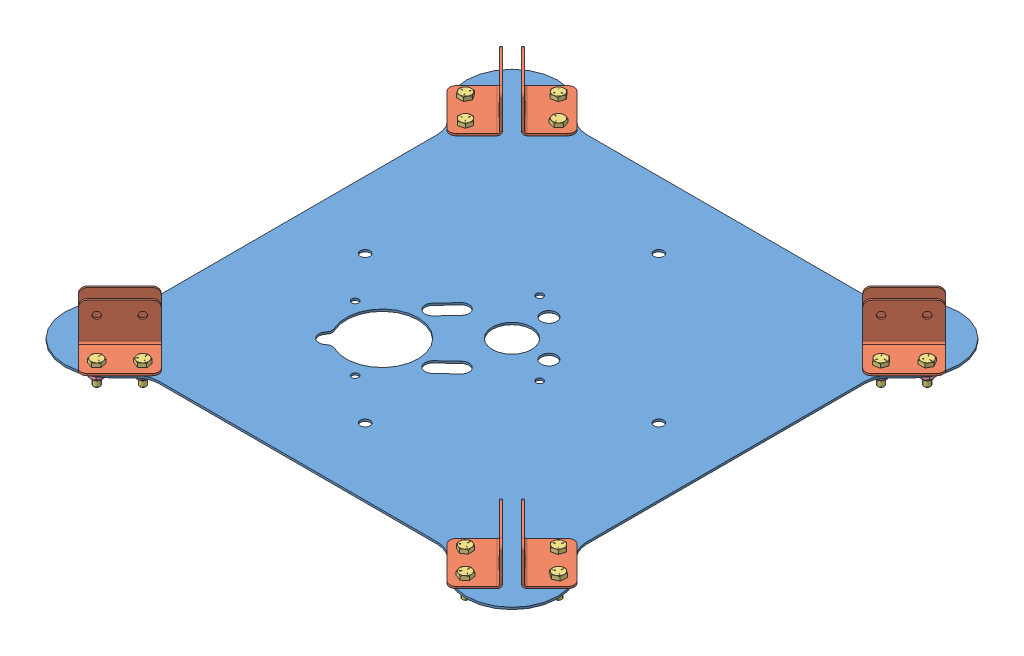
SolidWorks assembly GE-22413, configuration Default. Lengths in mm.
Overall size (485.29 55.25 485.29).
41 component instances, 4 part files, 91 mates.
Components (placement in the parent):
- GE-22412-1: GE-22412 [Default] at origin size (479.54 1.99 479.54)
- GE-22301-2: GE-22301 [Default] at (-195.5002 1.9939 186.1607) x (0.707107 0 -0.707107) z (0 1 0) size (57.15 38.1 38.1)
- GE-22301-17: GE-22301 [Default] at (-186.1607 1.9939 195.5002) x (0.707107 0 -0.707107) z (0.707107 0 0.707107) size (57.15 38.1 38.1)
- GE-22301-1: GE-22301 [Default] at (195.5002 1.9939 -186.1607) x (0.707107 0 -0.707107) z (0.707107 0 0.707107) size (57.15 38.1 38.1)
- GE-22301-20: GE-22301 [Default] at (186.1607 1.9939 195.5002) x (-0.707107 0 -0.707107) z (0 1 0) size (57.15 38.1 38.1)
- GE-22301-22: GE-22301 [Default] at (195.5002 1.9939 186.1607) x (0.707107 0 0.707107) z (0 1 0) size (57.15 38.1 38.1)
- GE-22301-25: GE-22301 [Default] at (186.1607 1.9939 -195.5002) x (0.707107 0 -0.707107) z (0 1 0) size (57.15 38.1 38.1)
- GE-22301-27: GE-22301 [Default] at (-186.1607 1.9939 -195.5002) x (0.707107 0 0.707107) z (0 1 0) size (57.15 38.1 38.1)
- GE-22301-29: GE-22301 [Default] at (-195.5002 1.9939 -186.1607) x (-0.707107 0 -0.707107) z (0 1 0) size (57.15 38.1 38.1)
- hex_.25_20_0.75-1: hex_.25_20_0.75 [Default] at (224.686 -3.6493 -179.4255) x (0 -1 0) z (0 0 1) size (23.02 12.83 11.11)
- nylock_.25_20-1: nylock_.25_20 [Default] at (224.686 0 -179.4255) x (1 0 0) z (0 0 -1) size (11.11 7.94 12.83)
- hex_.25_20_0.75-2: hex_.25_20_0.75 [Default] at (202.2354 -3.6493 -156.9749) x (0 -1 0) z (0.188455 0 0.982082) size (23.02 12.83 11.11)
- nylock_.25_20-2: nylock_.25_20 [Default] at (202.2354 0 -156.9749) x (0.982082 0 -0.188455) z (-0.188455 0 -0.982082) size (11.11 7.94 12.83)
- hex_.25_20_0.75-4: hex_.25_20_0.75 [Default] at (179.4255 -3.6493 -224.686) x (0 -1 0) z (0.370156 0 0.92897) size (23.02 12.83 11.11)
- nylock_.25_20-4: nylock_.25_20 [Default] at (179.4255 0 -224.686) x (0.92897 0 -0.370156) z (-0.370156 0 -0.92897) size (11.11 7.94 12.83)
- hex_.25_20_0.75-6: hex_.25_20_0.75 [Default] at (156.9749 -3.6493 -202.2354) x (0 -1 0) z (0.561714 0 0.827332) size (23.02 12.83 11.11)
- nylock_.25_20-6: nylock_.25_20 [Default] at (156.9749 0 -202.2354) x (0.827332 0 -0.561714) z (-0.561714 0 -0.827332) size (11.11 7.94 12.83)
- hex_.25_20_0.75-8: hex_.25_20_0.75 [Default] at (-156.9749 -3.6493 -202.2354) x (0 -1 0) z (0.740013 0 0.672593) size (23.02 12.83 11.11)
- nylock_.25_20-8: nylock_.25_20 [Default] at (-156.9749 0 -202.2354) x (0.672593 0 -0.740013) z (-0.740013 0 -0.672593) size (11.11 7.94 12.83)
- hex_.25_20_0.75-25: hex_.25_20_0.75 [Default] at (-224.686 -3.6493 -179.4255) x (0 -1 0) z (0.879216 0 0.476424) size (23.02 12.83 11.11)
- nylock_.25_20-10: nylock_.25_20 [Default] at (-224.686 0 -179.4255) x (0.476424 0 -0.879216) z (-0.879216 0 -0.476424) size (11.11 7.94 12.83)
- hex_.25_20_0.75-31: hex_.25_20_0.75 [Default] at (-202.2354 -3.6493 -156.9749) x (0 -1 0) z (0.963756 0 0.266785) size (23.02 12.83 11.11)
- nylock_.25_20-12: nylock_.25_20 [Default] at (-202.2354 0 -156.9749) x (0.266785 0 -0.963756) z (-0.963756 0 -0.266785) size (11.11 7.94 12.83)
- hex_.25_20_0.75-28: hex_.25_20_0.75 [Default] at (-224.686 -3.6493 179.4255) x (0 -1 0) z (0.997054 0 0.076699) size (23.02 12.83 11.11)
- nylock_.25_20-14: nylock_.25_20 [Default] at (-224.686 0 179.4255) x (0.076699 0 -0.997054) z (-0.997054 0 -0.076699) size (11.11 7.94 12.83)
- hex_.25_20_0.75-27: hex_.25_20_0.75 [Default] at (-202.2354 -3.6493 156.9749) x (0 -1 0) z (0.997612 0 -0.069065) size (23.02 12.83 11.11)
- nylock_.25_20-16: nylock_.25_20 [Default] at (-202.2354 0 156.9749) x (-0.069065 0 -0.997612) z (-0.997612 0 0.069065) size (11.11 7.94 12.83)
- hex_.25_20_0.75-26: hex_.25_20_0.75 [Default] at (-156.9749 -3.6493 202.2354) x (0 -1 0) z (0.987353 0 -0.158535) size (23.02 12.83 11.11)
- nylock_.25_20-18: nylock_.25_20 [Default] at (-156.9749 0 202.2354) x (-0.158535 0 -0.987353) z (-0.987353 0 0.158535) size (11.11 7.94 12.83)
- hex_.25_20_0.75-30: hex_.25_20_0.75 [Default] at (-179.4255 -3.6493 224.686) x (0 -1 0) z (0.982082 0 -0.188455) size (23.02 12.83 11.11)
- nylock_.25_20-20: nylock_.25_20 [Default] at (-179.4255 0 224.686) x (-0.188455 0 -0.982082) z (-0.982082 0 0.188455) size (11.11 7.94 12.83)
- hex_.25_20_0.75-32: hex_.25_20_0.75 [Default] at (179.4255 -3.6493 224.686) x (0 -1 0) z (0.987353 0 -0.158535) size (23.02 12.83 11.11)
- nylock_.25_20-22: nylock_.25_20 [Default] at (179.4255 0 224.686) x (-0.158535 0 -0.987353) z (-0.987353 0 0.158535) size (11.11 7.94 12.83)
- hex_.25_20_0.75-24: hex_.25_20_0.75 [Default] at (156.9749 -3.6493 202.2354) x (0 -1 0) z (0.997612 0 -0.069065) size (23.02 12.83 11.11)
- nylock_.25_20-24: nylock_.25_20 [Default] at (156.9749 0 202.2354) x (-0.069065 0 -0.997612) z (-0.997612 0 0.069065) size (11.11 7.94 12.83)
- hex_.25_20_0.75-33: hex_.25_20_0.75 [Default] at (224.686 -3.6493 179.4255) x (0 -1 0) z (0.997054 0 0.076699) size (23.02 12.83 11.11)
- nylock_.25_20-26: nylock_.25_20 [Default] at (224.686 0 179.4255) x (0.076699 0 -0.997054) z (-0.997054 0 -0.076699) size (11.11 7.94 12.83)
- hex_.25_20_0.75-29: hex_.25_20_0.75 [Default] at (202.2354 -3.6493 156.9749) x (0 -1 0) z (0.963756 0 0.266785) size (23.02 12.83 11.11)
- nylock_.25_20-28: nylock_.25_20 [Default] at (202.2354 0 156.9749) x (0.266785 0 -0.963756) z (-0.963756 0 -0.266785) size (11.11 7.94 12.83)
- hex_.25_20_0.75-34: hex_.25_20_0.75 [Default] at (-179.4255 -3.6493 -224.686) x (0 -1 0) z (0.188455 0 0.982082) size (23.02 12.83 11.11)
- nylock_.25_20-30: nylock_.25_20 [Default] at (-179.4255 0 -224.686) x (0.982082 0 -0.188455) z (-0.188455 0 -0.982082) size (11.11 7.94 12.83)
Mates (geometry in assembly coordinates):
- Coincident1: coincident anti-aligned: plane of GE-22412-1 through (0 0 0) normal (0 -1 0)
- Coincident2: coincident aligned: plane of GE-22412-1 through (0 0 0) normal (0 0 1)
- Coincident3: coincident aligned: plane of GE-22412-1 through (0 0 0) normal (1 0 0)
- Concentric1: concentric aligned: cylinder of GE-22412-1 through (-224.686 1.9939 179.4255) axis (0 1 0) radius 3.3782; cylinder of GE-22301-2 through (-224.686 3.8913 179.4255) axis (0 1 0) radius 3.3782
- Concentric2: concentric aligned: cylinder of GE-22412-1 through (-202.2354 1.9939 156.9749) axis (0 1 0) radius 3.3782; cylinder of GE-22301-2 through (-202.2354 3.8913 156.9749) axis (0 1 0) radius 3.3782
- Coincident4: coincident anti-aligned: plane of GE-22412-1 through (0 1.9939 0) normal (0 1 0); plane of GE-22301-2 through (-195.5002 1.9939 186.1607) normal (0 -1 0)
- Concentric3: concentric aligned: cylinder of GE-22412-1 through (-156.9749 1.9939 202.2354) axis (0 1 0) radius 3.3782; cylinder of GE-22301-17 through (-156.9749 3.8913 202.2354) axis (0 1 0) radius 3.3782
- Concentric4: concentric aligned: cylinder of GE-22412-1 through (-179.4255 1.9939 224.686) axis (0 1 0) radius 3.3782; cylinder of GE-22301-17 through (-179.4255 3.8913 224.686) axis (0 1 0) radius 3.3782
- Coincident5: coincident anti-aligned: plane of GE-22412-1 through (0 1.9939 0) normal (0 1 0); plane of GE-22301-17 through (-186.1607 1.9939 195.5002) normal (0 -1 0)
- Coincident12: coincident anti-aligned: plane of GE-22412-1 through (0 1.9939 0) normal (0 1 0); plane of GE-22301-1 through (195.5002 1.9939 -186.1607) normal (0 -1 0)
- Concentric17: concentric aligned: cylinder of GE-22412-1 through (202.2354 1.9939 -156.9749) axis (0 1 0) radius 3.3782; cylinder of GE-22301-1 through (202.2354 3.8913 -156.9749) axis (0 1 0) radius 3.3782
- Concentric18: concentric aligned: cylinder of GE-22412-1 through (224.686 1.9939 -179.4255) axis (0 1 0) radius 3.3782; cylinder of GE-22301-1 through (224.686 3.8913 -179.4255) axis (0 1 0) radius 3.3782
- Concentric19: concentric aligned: cylinder of GE-22412-1 through (179.4255 1.9939 224.686) axis (0 1 0) radius 3.3782; cylinder of GE-22301-20 through (179.4255 3.8913 224.686) axis (0 1 0) radius 3.3782
- Concentric20: concentric aligned: cylinder of GE-22412-1 through (156.9749 1.9939 202.2354) axis (0 1 0) radius 3.3782; cylinder of GE-22301-20 through (156.9749 3.8913 202.2354) axis (0 1 0) radius 3.3782
- Coincident13: coincident anti-aligned: plane of GE-22412-1 through (0 1.9939 0) normal (0 1 0); plane of GE-22301-20 through (186.1607 1.9939 195.5002) normal (0 -1 0)
- Concentric21: concentric aligned: cylinder of GE-22412-1 through (202.2354 1.9939 156.9749) axis (0 1 0) radius 3.3782; cylinder of GE-22301-22 through (202.2354 3.8913 156.9749) axis (0 1 0) radius 3.3782
- Concentric22: concentric aligned: cylinder of GE-22412-1 through (224.686 1.9939 179.4255) axis (0 1 0) radius 3.3782; cylinder of GE-22301-22 through (224.686 3.8913 179.4255) axis (0 1 0) radius 3.3782
- Coincident14: coincident anti-aligned: plane of GE-22412-1 through (0 1.9939 0) normal (0 1 0); plane of GE-22301-22 through (195.5002 1.9939 186.1607) normal (0 -1 0)
- Concentric25: concentric aligned: cylinder of GE-22412-1 through (156.9749 1.9939 -202.2354) axis (0 1 0) radius 3.3782; cylinder of GE-22301-25 through (156.9749 3.8913 -202.2354) axis (0 1 0) radius 3.3782
- Concentric26: concentric aligned: cylinder of GE-22412-1 through (179.4255 1.9939 -224.686) axis (0 1 0) radius 3.3782; cylinder of GE-22301-25 through (179.4255 3.8913 -224.686) axis (0 1 0) radius 3.3782
- Coincident15: coincident anti-aligned: plane of GE-22412-1 through (0 1.9939 0) normal (0 1 0); plane of GE-22301-25 through (186.1607 1.9939 -195.5002) normal (0 -1 0)
- Concentric27: concentric aligned: cylinder of GE-22412-1 through (-179.4255 1.9939 -224.686) axis (0 1 0) radius 3.3782; cylinder of GE-22301-27 through (-179.4255 3.8913 -224.686) axis (0 1 0) radius 3.3782
- Concentric28: concentric aligned: cylinder of GE-22412-1 through (-156.9749 1.9939 -202.2354) axis (0 1 0) radius 3.3782; cylinder of GE-22301-27 through (-156.9749 3.8913 -202.2354) axis (0 1 0) radius 3.3782
- Coincident16: coincident anti-aligned: plane of GE-22412-1 through (0 1.9939 0) normal (0 1 0); plane of GE-22301-27 through (-186.1607 1.9939 -195.5002) normal (0 -1 0)
- Concentric29: concentric aligned: cylinder of GE-22412-1 through (-202.2354 1.9939 -156.9749) axis (0 1 0) radius 3.3782; cylinder of GE-22301-29 through (-202.2354 3.8913 -156.9749) axis (0 1 0) radius 3.3782
- Concentric30: concentric aligned: cylinder of GE-22412-1 through (-224.686 1.9939 -179.4255) axis (0 1 0) radius 3.3782; cylinder of GE-22301-29 through (-224.686 3.8913 -179.4255) axis (0 1 0) radius 3.3782
- Coincident17: coincident anti-aligned: plane of GE-22412-1 through (0 1.9939 0) normal (0 1 0); plane of GE-22301-29 through (-195.5002 1.9939 -186.1607) normal (0 -1 0)
- Concentric31: concentric anti-aligned: cylinder of GE-22301-1 through (224.686 3.8913 -179.4255) axis (0 1 0) radius 3.3782; cylinder of hex_.25_20_0.75-1 through (224.686 3.8913 -179.4255) axis (0 -1 0) radius 3.175
- Coincident18: coincident anti-aligned: plane of GE-22301-1 through (195.5002 3.8913 -186.1607) normal (0 1 0); plane of hex_.25_20_0.75-1 through (227.8939 3.8913 -173.8693) normal (0 -1 0)
- Concentric32: concentric aligned: cylinder of hex_.25_20_0.75-1 through (224.686 3.8913 -179.4255) axis (0 -1 0) radius 3.175; cylinder of nylock_.25_20-1 through (224.686 0 -179.4255) axis (0 -1 0) radius 3.175
- Coincident19: coincident anti-aligned: plane of GE-22412-1 through (0 0 0) normal (0 -1 0); plane of nylock_.25_20-1 through (224.686 0 -179.4255) normal (0 1 0)
- Concentric33: concentric aligned: cylinder of hex_.25_20_0.75-2 through (202.2354 3.8913 -156.9749) axis (0 -1 0) radius 3.175; cylinder of nylock_.25_20-2 through (202.2354 0 -156.9749) axis (0 -1 0) radius 3.175
- Concentric34: concentric anti-aligned: cylinder of GE-22301-1 through (202.2354 3.8913 -156.9749) axis (0 1 0) radius 3.3782; cylinder of hex_.25_20_0.75-2 through (202.2354 3.8913 -156.9749) axis (0 -1 0) radius 3.175
- Coincident20: coincident anti-aligned: plane of GE-22301-1 through (195.5002 3.8913 -186.1607) normal (0 1 0); plane of hex_.25_20_0.75-2 through (206.4329 3.8913 -152.1227) normal (0 -1 0)
- Coincident21: coincident anti-aligned: plane of GE-22412-1 through (0 0 0) normal (0 -1 0); plane of nylock_.25_20-2 through (202.2354 0 -156.9749) normal (0 1 0)
- Concentric36: concentric aligned: cylinder of hex_.25_20_0.75-4 through (179.4255 3.8913 -224.686) axis (0 -1 0) radius 3.175; cylinder of nylock_.25_20-4 through (179.4255 0 -224.686) axis (0 -1 0) radius 3.175
- Concentric37: concentric anti-aligned: cylinder of GE-22301-25 through (179.4255 3.8913 -224.686) axis (0 1 0) radius 3.3782; cylinder of hex_.25_20_0.75-4 through (179.4255 3.8913 -224.686) axis (0 -1 0) radius 3.175
- Coincident22: coincident anti-aligned: plane of GE-22301-25 through (186.1607 3.8913 -195.5002) normal (0 1 0); plane of hex_.25_20_0.75-4 through (184.4622 3.8913 -220.7118) normal (0 -1 0)
- Coincident23: coincident anti-aligned: plane of GE-22412-1 through (0 0 0) normal (0 -1 0); plane of nylock_.25_20-4 through (179.4255 0 -224.686) normal (0 1 0)
- Concentric39: concentric aligned: cylinder of hex_.25_20_0.75-6 through (156.9749 3.8913 -202.2354) axis (0 -1 0) radius 3.175; cylinder of nylock_.25_20-6 through (156.9749 0 -202.2354) axis (0 -1 0) radius 3.175
- Concentric40: concentric anti-aligned: cylinder of GE-22301-25 through (156.9749 3.8913 -202.2354) axis (0 1 0) radius 3.3782; cylinder of hex_.25_20_0.75-6 through (156.9749 3.8913 -202.2354) axis (0 -1 0) radius 3.175
- Coincident24: coincident anti-aligned: plane of GE-22301-25 through (186.1607 3.8913 -195.5002) normal (0 1 0); plane of hex_.25_20_0.75-6 through (162.7499 3.8913 -199.4404) normal (0 -1 0)
- Coincident25: coincident anti-aligned: plane of GE-22412-1 through (0 0 0) normal (0 -1 0); plane of nylock_.25_20-6 through (156.9749 0 -202.2354) normal (0 1 0)
- Concentric42: concentric aligned: cylinder of hex_.25_20_0.75-8 through (-156.9749 3.8913 -202.2354) axis (0 -1 0) radius 3.175; cylinder of nylock_.25_20-8 through (-156.9749 0 -202.2354) axis (0 -1 0) radius 3.175
- Concentric43: concentric anti-aligned: cylinder of GE-22301-27 through (-156.9749 3.8913 -202.2354) axis (0 1 0) radius 3.3782; cylinder of hex_.25_20_0.75-8 through (-156.9749 3.8913 -202.2354) axis (0 -1 0) radius 3.175
- Coincident26: coincident anti-aligned: plane of GE-22301-27 through (-186.1607 3.8913 -195.5002) normal (0 1 0); plane of hex_.25_20_0.75-8 through (-150.7056 3.8913 -200.8722) normal (0 -1 0)
- Coincident27: coincident anti-aligned: plane of GE-22412-1 through (0 0 0) normal (0 -1 0); plane of nylock_.25_20-8 through (-156.9749 0 -202.2354) normal (0 1 0)
- Concentric45: concentric aligned: cylinder of hex_.25_20_0.75-25 through (-224.686 3.8913 -179.4255) axis (0 -1 0) radius 3.175; cylinder of nylock_.25_20-10 through (-224.686 0 -179.4255) axis (0 -1 0) radius 3.175
- Concentric46: concentric anti-aligned: cylinder of GE-22301-29 through (-224.686 3.8913 -179.4255) axis (0 1 0) radius 3.3782; cylinder of hex_.25_20_0.75-25 through (-224.686 3.8913 -179.4255) axis (0 -1 0) radius 3.175
- Coincident28: coincident anti-aligned: plane of GE-22301-29 through (-195.5002 3.8913 -186.1607) normal (0 1 0); plane of hex_.25_20_0.75-25 through (-218.2725 3.8913 -179.5988) normal (0 -1 0)
- Coincident29: coincident anti-aligned: plane of GE-22412-1 through (0 0 0) normal (0 -1 0); plane of nylock_.25_20-10 through (-224.686 0 -179.4255) normal (0 1 0)
- Concentric48: concentric aligned: cylinder of hex_.25_20_0.75-31 through (-202.2354 3.8913 -156.9749) axis (0 -1 0) radius 3.175; cylinder of nylock_.25_20-12 through (-202.2354 0 -156.9749) axis (0 -1 0) radius 3.175
- Concentric49: concentric anti-aligned: cylinder of GE-22301-29 through (-202.2354 3.8913 -156.9749) axis (0 1 0) radius 3.3782; cylinder of hex_.25_20_0.75-31 through (-202.2354 3.8913 -156.9749) axis (0 -1 0) radius 3.175
- Coincident30: coincident anti-aligned: plane of GE-22301-29 through (-195.5002 3.8913 -186.1607) normal (0 1 0); plane of hex_.25_20_0.75-31 through (-196.0247 3.8913 -158.5842) normal (0 -1 0)
- Coincident31: coincident anti-aligned: plane of GE-22412-1 through (0 0 0) normal (0 -1 0); plane of nylock_.25_20-12 through (-202.2354 0 -156.9749) normal (0 1 0)
- Concentric51: concentric aligned: cylinder of hex_.25_20_0.75-28 through (-224.686 3.8913 179.4255) axis (0 -1 0) radius 3.175; cylinder of nylock_.25_20-14 through (-224.686 0 179.4255) axis (0 -1 0) radius 3.175
- Concentric52: concentric anti-aligned: cylinder of GE-22301-2 through (-224.686 3.8913 179.4255) axis (0 1 0) radius 3.3782; cylinder of hex_.25_20_0.75-28 through (-224.686 3.8913 179.4255) axis (0 -1 0) radius 3.175
- Coincident32: coincident anti-aligned: plane of GE-22301-2 through (-195.5002 3.8913 186.1607) normal (0 1 0); plane of hex_.25_20_0.75-28 through (-218.9001 3.8913 176.6532) normal (0 -1 0)
- Coincident33: coincident anti-aligned: plane of GE-22412-1 through (0 0 0) normal (0 -1 0); plane of nylock_.25_20-14 through (-224.686 0 179.4255) normal (0 1 0)
- Concentric54: concentric aligned: cylinder of hex_.25_20_0.75-27 through (-202.2354 3.8913 156.9749) axis (0 -1 0) radius 3.175; cylinder of nylock_.25_20-16 through (-202.2354 0 156.9749) axis (0 -1 0) radius 3.175
- Concentric55: concentric anti-aligned: cylinder of GE-22301-2 through (-202.2354 3.8913 156.9749) axis (0 1 0) radius 3.3782; cylinder of hex_.25_20_0.75-27 through (-202.2354 3.8913 156.9749) axis (0 -1 0) radius 3.175
- Coincident34: coincident anti-aligned: plane of GE-22301-2 through (-195.5002 3.8913 186.1607) normal (0 1 0); plane of hex_.25_20_0.75-27 through (-196.9139 3.8913 153.3909) normal (0 -1 0)
- Coincident35: coincident anti-aligned: plane of GE-22412-1 through (0 0 0) normal (0 -1 0); plane of nylock_.25_20-16 through (-202.2354 0 156.9749) normal (0 1 0)
- Concentric57: concentric aligned: cylinder of hex_.25_20_0.75-26 through (-156.9749 3.8913 202.2354) axis (0 -1 0) radius 3.175; cylinder of nylock_.25_20-18 through (-156.9749 0 202.2354) axis (0 -1 0) radius 3.175
- Concentric58: concentric anti-aligned: cylinder of GE-22301-17 through (-156.9749 3.8913 202.2354) axis (0 1 0) radius 3.3782; cylinder of hex_.25_20_0.75-26 through (-156.9749 3.8913 202.2354) axis (0 -1 0) radius 3.175
- Coincident36: coincident anti-aligned: plane of GE-22301-17 through (-186.1607 3.8913 195.5002) normal (0 1 0); plane of hex_.25_20_0.75-26 through (-151.9975 3.8913 198.1872) normal (0 -1 0)
- Coincident37: coincident anti-aligned: plane of GE-22412-1 through (0 0 0) normal (0 -1 0); plane of nylock_.25_20-18 through (-156.9749 0 202.2354) normal (0 1 0)
- Concentric60: concentric aligned: cylinder of hex_.25_20_0.75-30 through (-179.4255 3.8913 224.686) axis (0 -1 0) radius 3.175; cylinder of nylock_.25_20-20 through (-179.4255 0 224.686) axis (0 -1 0) radius 3.175
- Concentric61: concentric anti-aligned: cylinder of GE-22301-17 through (-179.4255 3.8913 224.686) axis (0 1 0) radius 3.3782; cylinder of hex_.25_20_0.75-30 through (-179.4255 3.8913 224.686) axis (0 -1 0) radius 3.175
- Coincident38: coincident anti-aligned: plane of GE-22301-17 through (-186.1607 3.8913 195.5002) normal (0 1 0); plane of hex_.25_20_0.75-30 through (-174.5734 3.8913 220.4885) normal (0 -1 0)
- Coincident39: coincident anti-aligned: plane of GE-22412-1 through (0 0 0) normal (0 -1 0); plane of nylock_.25_20-20 through (-179.4255 0 224.686) normal (0 1 0)
- Concentric63: concentric aligned: cylinder of hex_.25_20_0.75-32 through (179.4255 3.8913 224.686) axis (0 -1 0) radius 3.175; cylinder of nylock_.25_20-22 through (179.4255 0 224.686) axis (0 -1 0) radius 3.175
- Concentric64: concentric anti-aligned: cylinder of GE-22301-20 through (179.4255 3.8913 224.686) axis (0 1 0) radius 3.3782; cylinder of hex_.25_20_0.75-32 through (179.4255 3.8913 224.686) axis (0 -1 0) radius 3.175
- Coincident40: coincident anti-aligned: plane of GE-22301-20 through (186.1607 3.8913 195.5002) normal (0 1 0); plane of hex_.25_20_0.75-32 through (184.4029 3.8913 220.6378) normal (0 -1 0)
- Coincident41: coincident anti-aligned: plane of GE-22412-1 through (0 0 0) normal (0 -1 0); plane of nylock_.25_20-22 through (179.4255 0 224.686) normal (0 1 0)
- Concentric66: concentric aligned: cylinder of hex_.25_20_0.75-24 through (156.9749 3.8913 202.2354) axis (0 -1 0) radius 3.175; cylinder of nylock_.25_20-24 through (156.9749 0 202.2354) axis (0 -1 0) radius 3.175
- Concentric67: concentric anti-aligned: cylinder of GE-22301-20 through (156.9749 3.8913 202.2354) axis (0 1 0) radius 3.3782; cylinder of hex_.25_20_0.75-24 through (156.9749 3.8913 202.2354) axis (0 -1 0) radius 3.175
- Coincident42: coincident anti-aligned: plane of GE-22301-20 through (186.1607 3.8913 195.5002) normal (0 1 0); plane of hex_.25_20_0.75-24 through (162.2963 3.8913 198.6514) normal (0 -1 0)
- Coincident43: coincident anti-aligned: plane of GE-22412-1 through (0 0 0) normal (0 -1 0); plane of nylock_.25_20-24 through (156.9749 0 202.2354) normal (0 1 0)
- Concentric69: concentric aligned: cylinder of hex_.25_20_0.75-33 through (224.686 3.8913 179.4255) axis (0 -1 0) radius 3.175; cylinder of nylock_.25_20-26 through (224.686 0 179.4255) axis (0 -1 0) radius 3.175
- Concentric70: concentric anti-aligned: cylinder of GE-22301-22 through (224.686 3.8913 179.4255) axis (0 1 0) radius 3.3782; cylinder of hex_.25_20_0.75-33 through (224.686 3.8913 179.4255) axis (0 -1 0) radius 3.175
- Coincident44: coincident anti-aligned: plane of GE-22301-22 through (195.5002 3.8913 186.1607) normal (0 1 0); plane of hex_.25_20_0.75-33 through (230.4719 3.8913 176.6532) normal (0 -1 0)
- Coincident45: coincident anti-aligned: plane of GE-22412-1 through (0 0 0) normal (0 -1 0); plane of nylock_.25_20-26 through (224.686 0 179.4255) normal (0 1 0)
- Concentric72: concentric aligned: cylinder of hex_.25_20_0.75-29 through (202.2354 3.8913 156.9749) axis (0 -1 0) radius 3.175; cylinder of nylock_.25_20-28 through (202.2354 0 156.9749) axis (0 -1 0) radius 3.175
- Concentric73: concentric anti-aligned: cylinder of GE-22301-22 through (202.2354 3.8913 156.9749) axis (0 1 0) radius 3.3782; cylinder of hex_.25_20_0.75-29 through (202.2354 3.8913 156.9749) axis (0 -1 0) radius 3.175
- Coincident46: coincident anti-aligned: plane of GE-22301-22 through (195.5002 3.8913 186.1607) normal (0 1 0); plane of hex_.25_20_0.75-29 through (208.4461 3.8913 155.3656) normal (0 -1 0)
- Coincident47: coincident anti-aligned: plane of GE-22412-1 through (0 0 0) normal (0 -1 0); plane of nylock_.25_20-28 through (202.2354 0 156.9749) normal (0 1 0)
- Concentric75: concentric aligned: cylinder of hex_.25_20_0.75-34 through (-179.4255 3.8913 -224.686) axis (0 -1 0) radius 3.175; cylinder of nylock_.25_20-30 through (-179.4255 0 -224.686) axis (0 -1 0) radius 3.175
- Concentric76: concentric anti-aligned: cylinder of GE-22301-27 through (-179.4255 3.8913 -224.686) axis (0 1 0) radius 3.3782; cylinder of hex_.25_20_0.75-34 through (-179.4255 3.8913 -224.686) axis (0 -1 0) radius 3.175
- Coincident48: coincident anti-aligned: plane of GE-22301-27 through (-186.1607 3.8913 -195.5002) normal (0 1 0); plane of hex_.25_20_0.75-34 through (-175.228 3.8913 -219.8339) normal (0 -1 0)
- Coincident49: coincident anti-aligned: plane of GE-22412-1 through (0 0 0) normal (0 -1 0); plane of nylock_.25_20-30 through (-179.4255 0 -224.686) normal (0 1 0)
